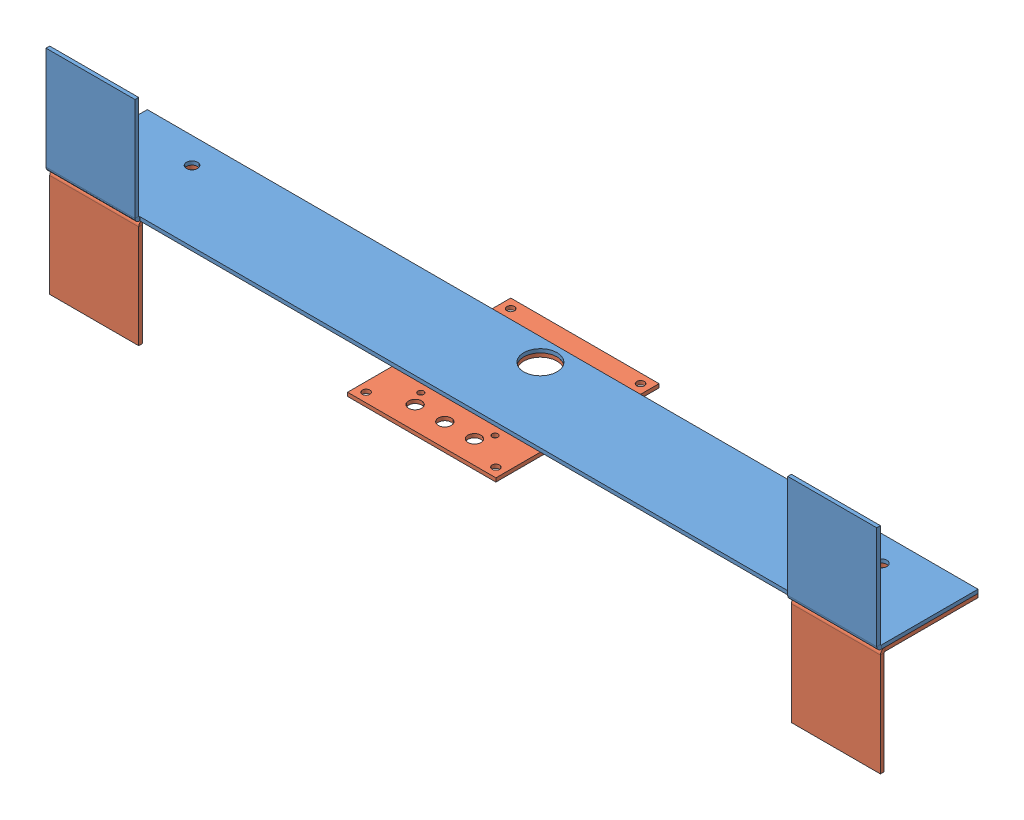
SolidWorks assembly Assem3, configuration Default. Lengths in mm.
Overall size (711.2 184.15 139.7).
2 component instances, 2 part files, 3 mates.
Components (placement in the parent):
- exterior wheel well-1: exterior wheel well [Default] at (45.5135 465.233 598.0526) size (711.2 92.07 86.72)
- interior wheel well-1: interior wheel well [Default] at (544.1643 456.888 594.8776) x (-1 0 0) z (0 0 1) size (711.2 92.08 139.7)
Mates (geometry in assembly coordinates):
- Coincident1: coincident anti-aligned: plane of exterior wheel well-1 through (-60.7611 461.0605 603.4051) normal (0 -1 0); plane of interior wheel well-1 through (650.4389 461.0605 603.4051) normal (0 1 0)
- Coincident2: coincident aligned: line of exterior wheel well-1 through (650.4389 461.0605 603.4051) axis (0 0 1); line of interior wheel well-1 through (650.4389 461.0605 603.4051) axis (0 0 1)
- Coincident4: coincident anti-aligned: plane of exterior wheel well-1 through (-60.7611 378.5105 686.9526) normal (0 0 -1); plane of interior wheel well-1 through (650.4389 540.4355 686.9526) normal (0 0 1)
